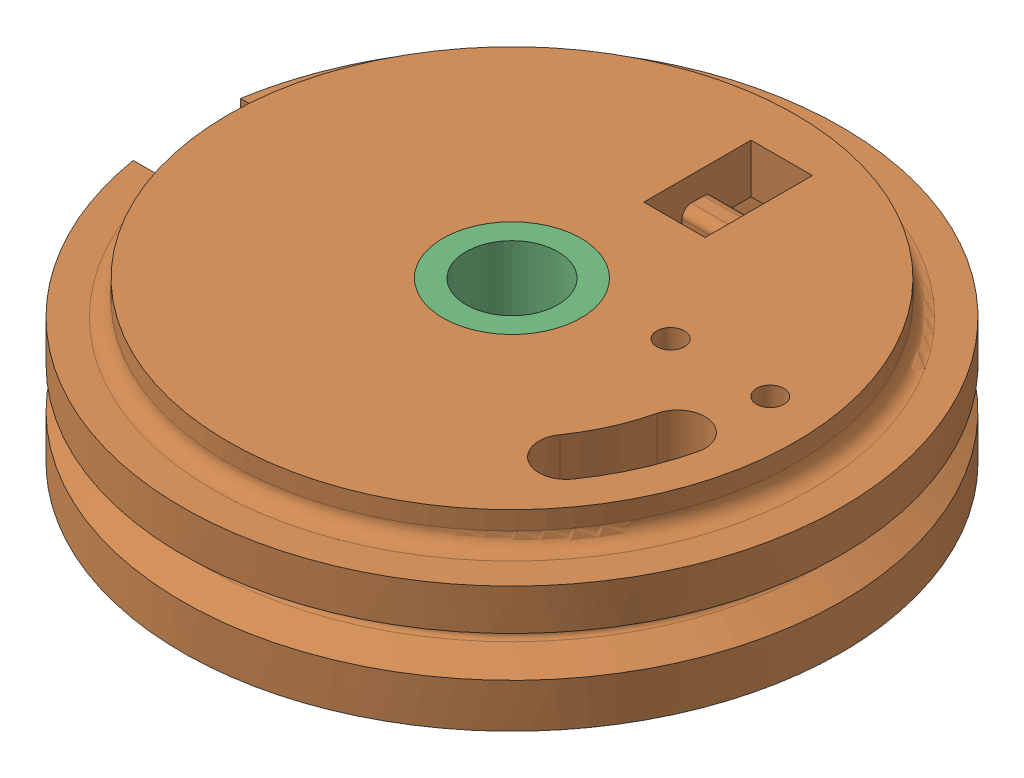
SolidWorks assembly floating_half_pulley_with_insert_and_press_fit_parts, configuration Default. Lengths in mm.
Overall size (42.72 10.4 43).
4 component instances, 3 part files, 0 mates.
Components (placement in the parent):
- floating_half_pulley_with_insert-1: floating_half_pulley_with_insert [Default] at origin size (42.72 10.4 43)
  - m3_heat_set_insert_94180A331_94180A331-1: m3_heat_set_insert_94180A331_94180A331 [Default] at (0 4.8 26.7112) x (0 -0.064302 0.99793) z (0 -0.99793 -0.064302) size (5.56 3.88 5.56)
  - half-pulley_Floating Half Pulley Underside-1: half-pulley_Floating Half Pulley Underside [Default] at (19.6031 8.8 26.7112) x (1 0 0) z (0 0 -1) size (42.72 10.4 43)
- 6mm_sleeve_bearing_6658K725_6658K725-1: 6mm_sleeve_bearing_6658K725_6658K725 [Default] at (19.6031 8 26.7112) x (0.690337 0 -0.723488) z (0 -1 0) size (9.02 9.02 6)
